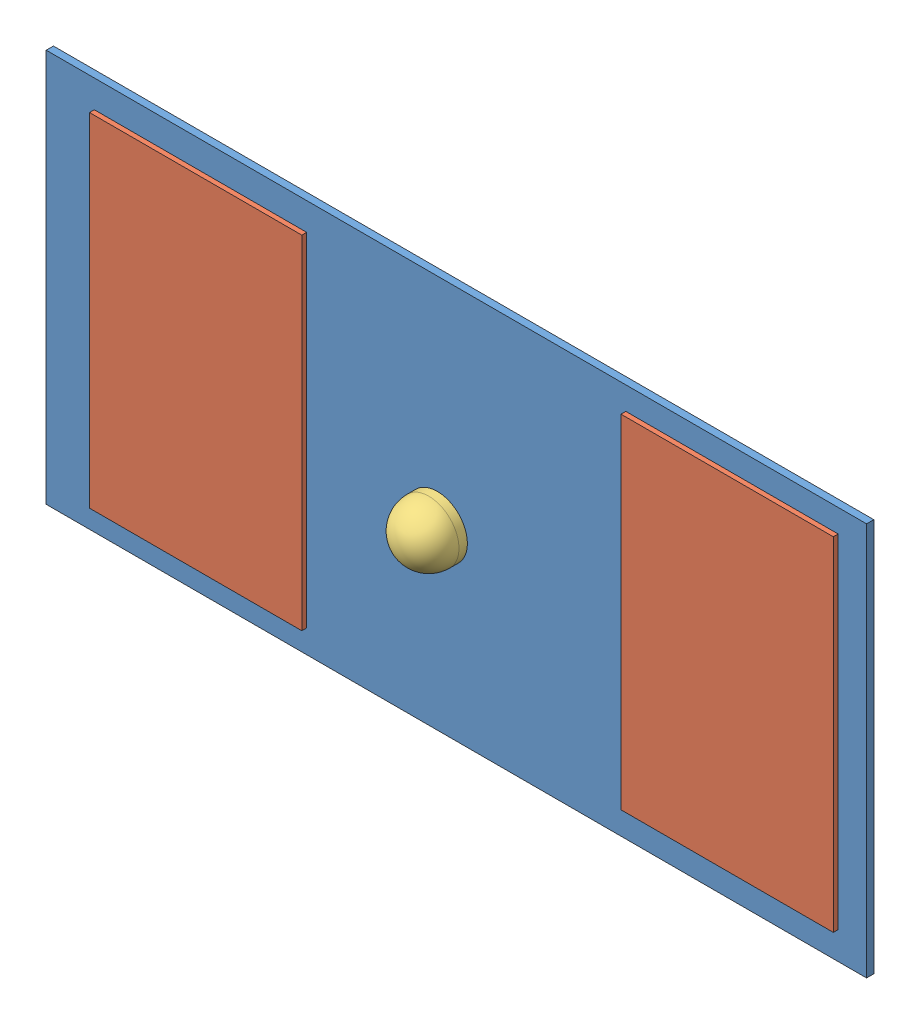
SolidWorks assembly Assem3, configuration Default. Lengths in mm.
Overall size (340 163 19).
4 component instances, 3 part files, 5 mates.
Components (placement in the parent):
- solar_Panel_Support-1: solar_Panel_Support [Default] at (118.3775 184.7431 260.5151) size (340 163 3)
- solar_Panel-1: solar_Panel [Default] at (12.3228 183.8446 265.5151) x (1 0 0) z (0 0 -1) size (88 142 5)
- solar_Panel-2: solar_Panel [Default] at (232.6014 185.7148 265.5151) x (1 0 0) z (0 0 -1) size (88 142 5)
- Light_sensor-1: Light_sensor [Default] at (110.4404 176.4535 263.5151) size (28 28 18)
Mates (geometry in assembly coordinates):
- Coincident1: coincident anti-aligned: plane of solar_Panel_Support-1 through (118.3775 184.7431 263.5151) normal (0 0 1); plane of solar_Panel-2 through (232.6014 185.7148 263.5151) normal (0 0 -1)
- Coincident2: coincident anti-aligned: plane of solar_Panel_Support-1 through (118.3775 184.7431 263.5151) normal (0 0 1); plane of solar_Panel-1 through (12.3228 183.8446 263.5151) normal (0 0 -1)
- Parallel1: parallel aligned: plane of solar_Panel_Support-1 through (-51.6225 266.2431 263.5151) normal (-1 0 0); plane of solar_Panel-1 through (-31.6772 112.8446 263.5151) normal (-1 0 0)
- Parallel2: parallel aligned: plane of solar_Panel_Support-1 through (288.3775 266.2431 263.5151) normal (1 0 0); plane of solar_Panel-2 through (276.6014 114.7148 263.5151) normal (1 0 0)
- Coincident5: coincident aligned: plane of solar_Panel_Support-1 through (118.3775 184.7431 263.5151) normal (0 0 1); plane of Light_sensor-1 through (110.4404 176.4535 263.5151) normal (0 0 1)
